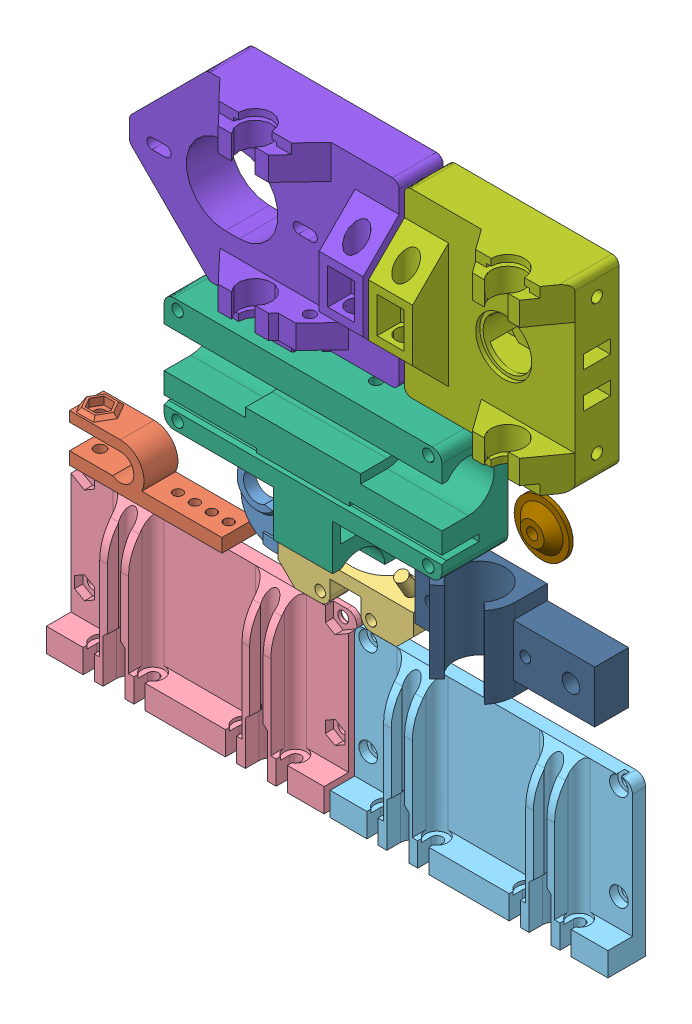
SolidWorks assembly RP-assembly, configuration Default. Lengths in mm.
Overall size (165.77 174.64 23.6).
10 component instances, 10 part files, 12 mates.
Components (placement in the parent):
- Belt Guide-1: Belt Guide [Default] at (8.8653 2.6934 0) size (11.5 29 3.5)
- EndStop-Holder-1: EndStop-Holder [Default] at (-36.7165 -26.052 0) size (45 15 10)
- Fan Holder-1: Fan Holder [Default] at (99.4668 -3.9465 0) size (40 19.22 7.05)
- nozzle-mount-front-1: nozzle-mount-front [Default] at (36.2744 -28.7726 11.15) x (-1 0 0) z (0 0 -1) size (82 46.39 11.15)
- nozzle-mount-rear-1: nozzle-mount-rear [Default] at (120.0421 -28.8272 11.15) x (-1 0 0) z (0 0 -1) size (82 46.39 11.15)
- x-carriage-1: x-carriage [Default] at (-2.6522 42.2552 11.6) x (0 0 -1) z (1 0 0) size (19.46 60 82)
- x-end-idler-1: x-end-idler [Default] at (61.8471 84.449 6.5) x (0 1 0) z (1 0 0) size (53.46 23.6 50.3)
- x-end-motor-1: x-end-motor [Default] at (10.4825 84.4888 0) x (1 0 0) z (0 -1 0) size (79.62 23.6 53.46)
- x-idler-cover-1: x-idler-cover [Default] at (90.5423 31.8206 1.2) size (16.2 16.2 4)
- Y-Bearing-Holder-1: Y-Bearing-Holder [Default] at (41.6153 5.2942 0) x (1 0 0) z (0 -1 0) size (53 17.76 24)
Mates (geometry in assembly coordinates):
- Coincident1: coincident anti-aligned: plane of x-carriage-1 through (79.3478 -7.2948 0) normal (0 0 -1); plane of assembly through (0 0 0) normal (0 0 1)
- Coincident2: coincident aligned: plane of nozzle-mount-front-1 through (-42.8756 -20.0226 0) normal (0 0 -1); plane of x-carriage-1 through (79.3478 -7.2948 0) normal (0 0 -1)
- Coincident3: coincident aligned: plane of nozzle-mount-rear-1 through (40.8921 -20.0772 0) normal (0 0 -1); plane of x-carriage-1 through (79.3478 -7.2948 0) normal (0 0 -1)
- Coincident4: coincident aligned: plane of x-carriage-1 through (79.3478 -7.2948 0) normal (0 0 -1); plane of x-end-motor-1 through (10.4825 84.4888 0) normal (0 0 -1)
- Coincident5: coincident aligned: plane of x-carriage-1 through (79.3478 -7.2948 0) normal (0 0 -1); plane of x-end-idler-1 through (112.1471 111.1777 0) normal (0 0 -1)
- Coincident6: coincident aligned: plane of x-carriage-1 through (79.3478 -7.2948 0) normal (0 0 -1); plane of Y-Bearing-Holder-1 through (41.6153 5.2942 0) normal (0 0 -1)
- Coincident7: coincident aligned: plane of x-carriage-1 through (79.3478 -7.2948 0) normal (0 0 -1); plane of x-idler-cover-1 through (90.5423 31.8206 0) normal (0 0 -1)
- Coincident8: coincident aligned: plane of Fan Holder-1 through (99.4668 -3.9465 0) normal (0 0 -1); plane of x-carriage-1 through (79.3478 -7.2948 0) normal (0 0 -1)
- Coincident12: coincident aligned: plane of EndStop-Holder-1 through (-25.0368 -5.9452 0) normal (0 0 -1); plane of x-carriage-1 through (79.3478 -7.2948 0) normal (0 0 -1)
- Coincident13: coincident aligned: plane of Belt Guide-1 through (8.8653 2.6934 0) normal (0 0 -1); plane of x-carriage-1 through (79.3478 -7.2948 0) normal (0 0 -1)
- Parallel1: parallel aligned: plane of nozzle-mount-front-1 through (-45.7256 -63.3726 3.15) normal (0 -1 0); plane of nozzle-mount-rear-1 through (38.0421 -63.4272 3.15) normal (0 -1 0)
- Parallel2: parallel aligned: plane of nozzle-mount-front-1 through (-45.7256 -63.3726 3.15) normal (0 -1 0); plane of x-carriage-1 through (-2.6522 21.0052 6.1646) normal (0 -1 0)
